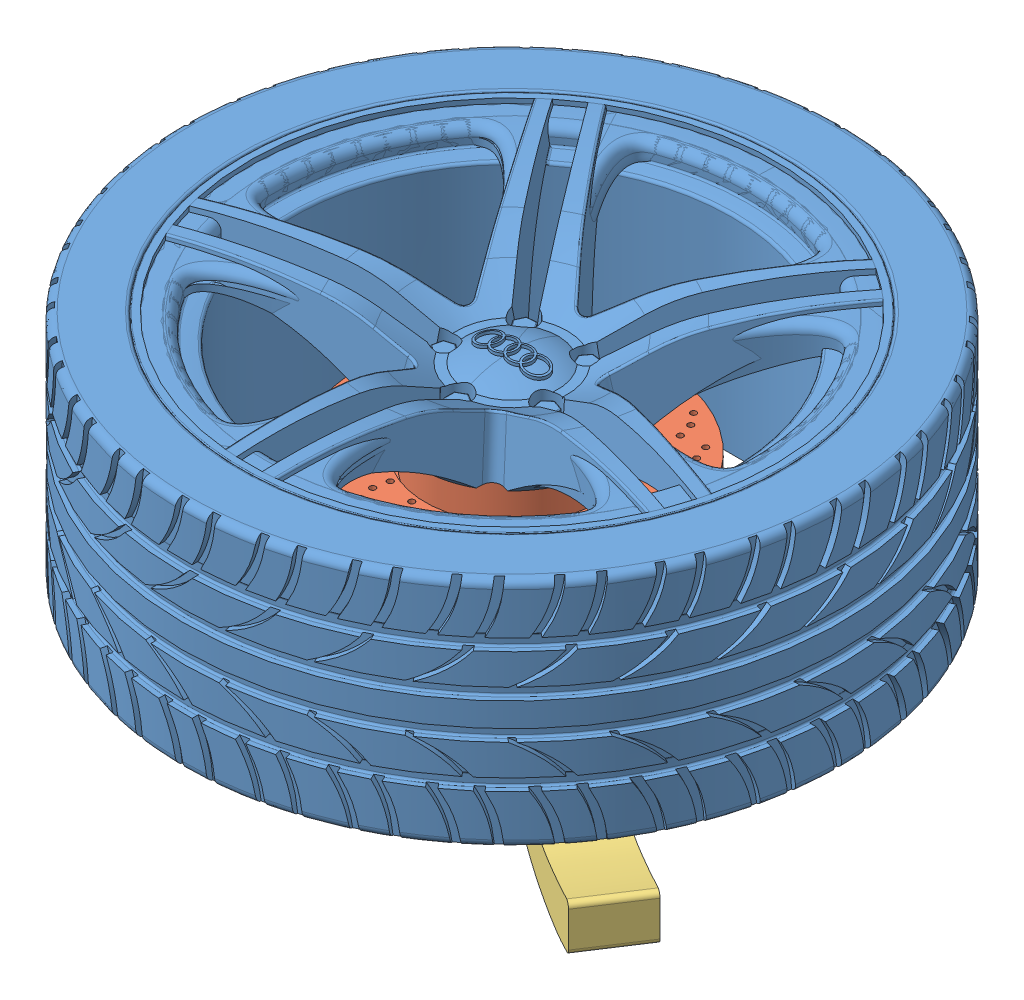
SolidWorks assembly Assem1, configuration Default. Lengths in mm.
Overall size (673.28 361.62 668.92).
3 component instances, 3 part files, 4 mates.
Components (placement in the parent):
- BÁNH XE-1: BÁNH XE [Varsayılan] at origin size (668.92 273.92 668.92)
- ĐĨA THẮNG-1: ĐĨA THẮNG [Default] at (0 809.9429 0) size (303 56.33 303)
- KHUNG TREO L-1: KHUNG TREO L [Default] at (0 713.4994 0) x (0 1 0) z (-0.546944 0 0.837169) size (231.48 449.46 221.1)
Mates (geometry in assembly coordinates):
- Concentric1: concentric anti-aligned: circle of BÁNH XE-1; circle of ĐĨA THẮNG-1
- Coincident1: coincident anti-aligned: plane of BÁNH XE-1 through (0 853.7729 0) normal (0 -1 0); plane of ĐĨA THẮNG-1 through (-35 853.7729 0) normal (0 1 0)
- Concentric2: concentric: circle of ĐĨA THẮNG-1; circle of KHUNG TREO L-1
- Coincident2: coincident anti-aligned: plane of BÁNH XE-1 through (0 853.7729 0) normal (0 -1 0); plane of KHUNG TREO L-1 through (0 853.7729 0) normal (0 1 0)
